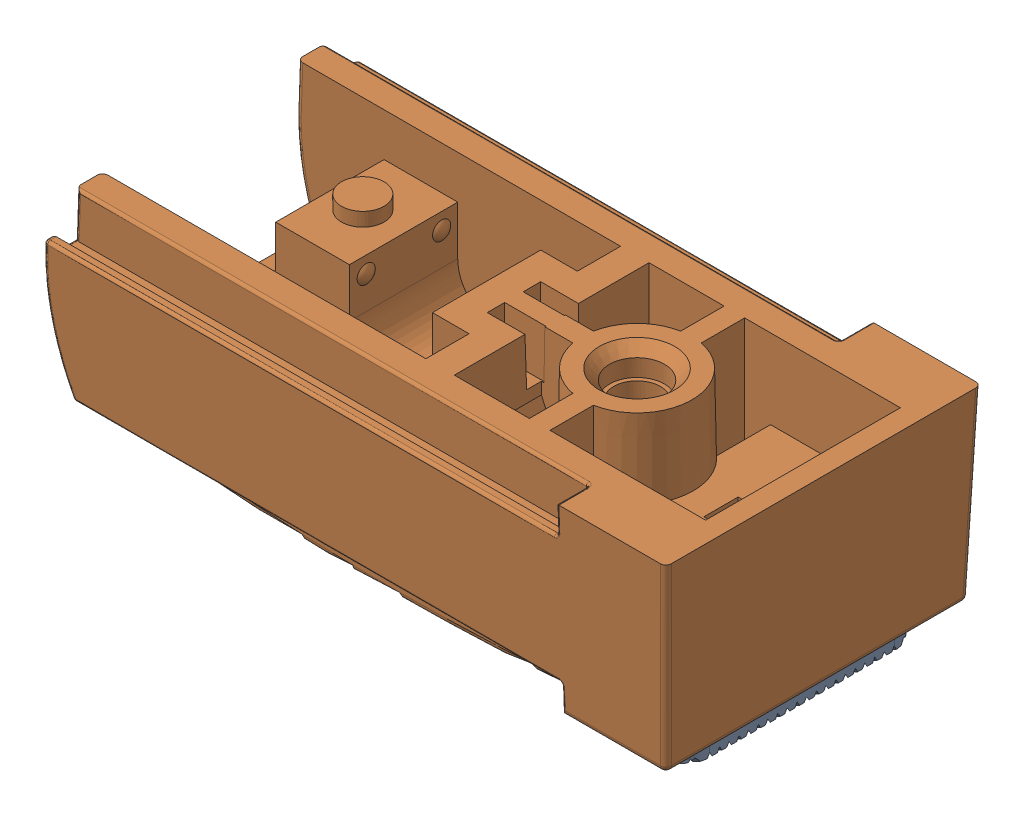
SolidWorks assembly 87646929, configuration По умолчанию. Lengths in mm.
Overall size (45.66 16.23 23.05).
2 component instances, 2 part files, 0 mates.
Components (placement in the parent):
- 60842027-1: 60842027 [По умолчанию] at (-13.1638 33.8211 0) x (-1 0 0) z (0 0 1) size (7.8 7.5 17.5)
- 87646929-1: 87646929 [По умолчанию] at (30.061 -56.7211 0) size (45.66 15.15 23.05)
